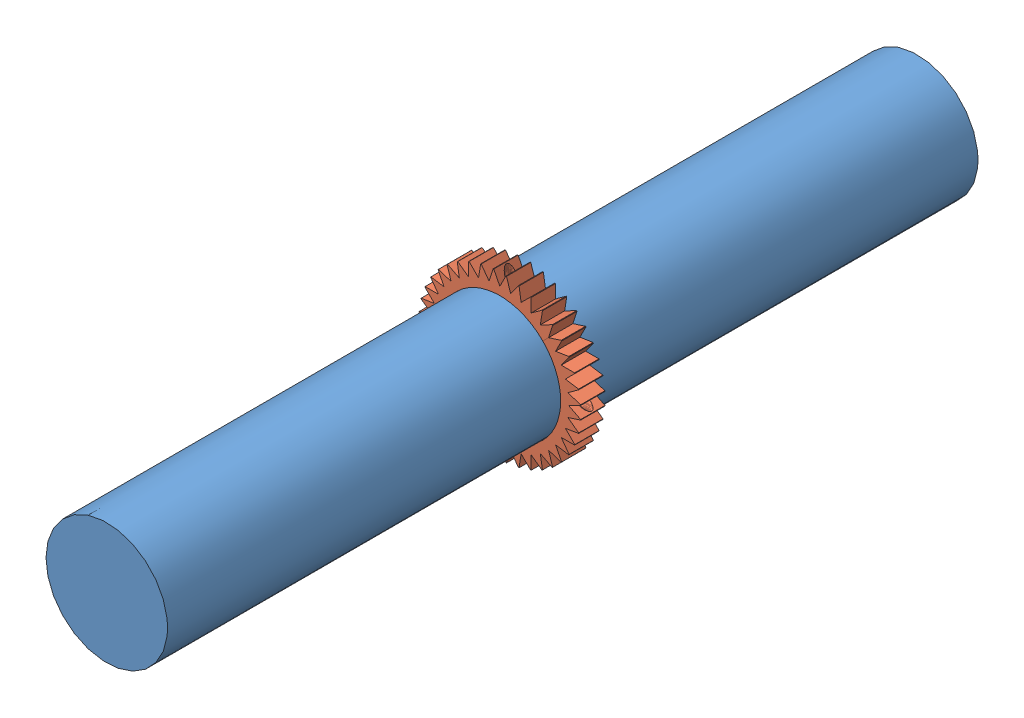
SolidWorks assembly 01-10-A-000-R00 Mechanisms, configuration Default. Lengths in mm.
Overall size (141.02 141.02 500).
4 component instances, 2 part files, 0 mates.
Components (placement in the parent):
- 01-11-A-000-R00 Driveshaft Gear Assembly-1: 01-11-A-000-R00 Driveshaft Gear Assembly [Default] at (-16.4297 15.0137 -1.5304) size (141.02 141.02 500)
  - 01-11-P-001-R00 Modified Driveshaft-2: 01-11-P-001-R00 Modified Driveshaft [Default] at origin size (75 75 500)
  - 01-11-P-002-R00 Driveshaft Tooth Converter-1: 01-11-P-002-R00 Driveshaft Tooth Converter [Default] x (0.707107 0.707107 0) z (0 0 1) size (99.72 49.86 15)
  - 01-11-P-002-R00 Driveshaft Tooth Converter-2: 01-11-P-002-R00 Driveshaft Tooth Converter [Default] x (-0.707107 -0.707107 0) z (0 0 1) size (99.72 49.86 15)
